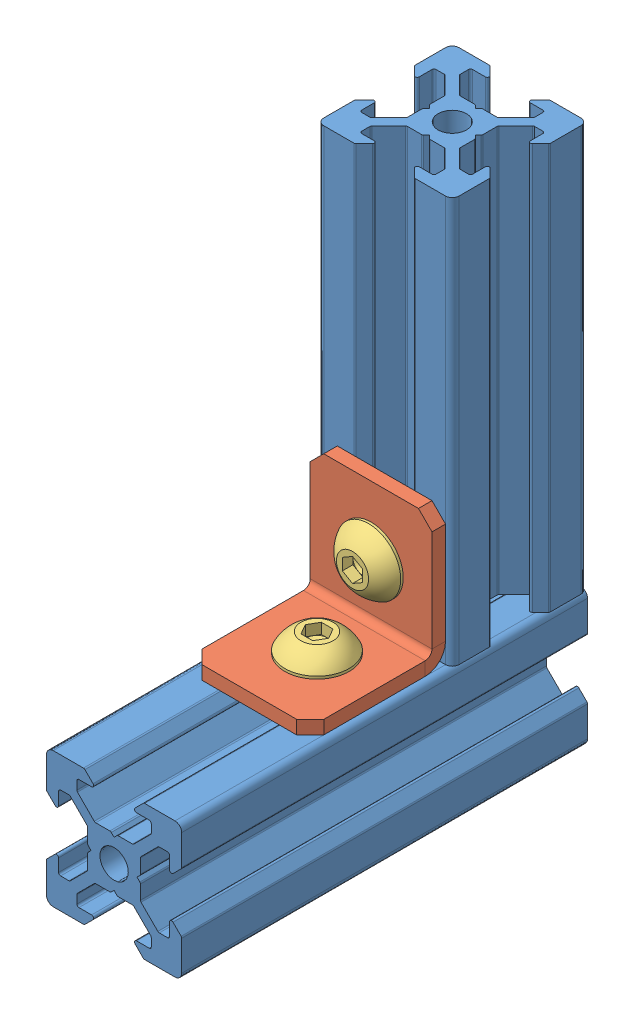
SolidWorks assembly Уголок 20 серия 1х2 20х20х18х2, configuration По умолчанию. Lengths in mm.
Overall size (20 80 60).
5 component instances, 3 part files, 10 mates.
Components (placement in the parent):
- 2020100-1: 2020100 [По умолчанию] at origin size (20 20 60)
- 2020100-2: 2020100 [По умолчанию] at (0 10 10) x (1 0 0) z (0 1 0) size (20 20 60)
- Уголок 20 серия 1х2 20х20х18х2-1: Уголок 20 серия 1х2 20х20х18х2 [По умолчанию] at (0 10 20) size (18 20 20)
- socket button head screw_iso-1: socket button head screw_iso [ISO 7380 - M5 x 10 - 10N] at (0 20 24.75) x (0 0 -1) z (1 0 0) size (12.75 9.5 9.5)
- socket button head screw_iso-2: socket button head screw_iso [ISO 7380 - M5 x 10 - 10N] at (0 14.75 30) x (0 -1 0) z (0 0 1) size (12.75 9.5 9.5)
Mates (geometry in assembly coordinates):
- Совпадение1: coincident aligned: plane of 2020100-1 through (10 10 60) normal (1 0 0); plane of 2020100-2 through (10 70 20) normal (1 0 0)
- Совпадение2: coincident anti-aligned: plane of 2020100-1 through (10 10 60) normal (0 1 0); plane of 2020100-2 through (0 10 10) normal (0 -1 0)
- Совпадение3: coincident anti-aligned: plane of 2020100-1 through (-10 10 60) normal (0 1 0); plane of Уголок 20 серия 1х2 20х20х18х2-1 through (0 10 20) normal (0 -1 0)
- Совпадение4: coincident anti-aligned: plane of 2020100-2 through (-10 70 20) normal (0 0 1); plane of Уголок 20 серия 1х2 20х20х18х2-1 through (0 10 20) normal (0 0 -1)
- Совпадение5: coincident aligned: plane of 2020100-1 through (0 0 0) normal (0 0 -1); plane of 2020100-2 through (-10 70 0) normal (0 0 -1)
- Расстояние1: distance = 1 mm aligned: plane of 2020100-1 through (10 10 60) normal (1 0 0); plane of Уголок 20 серия 1х2 20х20х18х2-1 through (9 10 40) normal (1 0 0)
- Концентричный1: concentric aligned: cylinder of Уголок 20 серия 1х2 20х20х18х2-1 through (0 20 22) axis (0 0 1) radius 2.75; cylinder of socket button head screw_iso-1 through (0 20 24.75) axis (0 0 1) radius 4.75
- Совпадение7: coincident anti-aligned: plane of Уголок 20 серия 1х2 20х20х18х2-1 through (0 10 22) normal (0 0 1); plane of socket button head screw_iso-1 through (0 22.5 22) normal (0 0 -1)
- Концентричный2: concentric aligned: cylinder of Уголок 20 серия 1х2 20х20х18х2-1 through (0 12 30) axis (0 1 0) radius 2.75; cylinder of socket button head screw_iso-2 through (0 14.75 30) axis (0 1 0) radius 4.75
- Совпадение8: coincident anti-aligned: plane of Уголок 20 серия 1х2 20х20х18х2-1 through (0 12 20) normal (0 1 0); plane of socket button head screw_iso-2 through (2.5 12 30) normal (0 -1 0)
